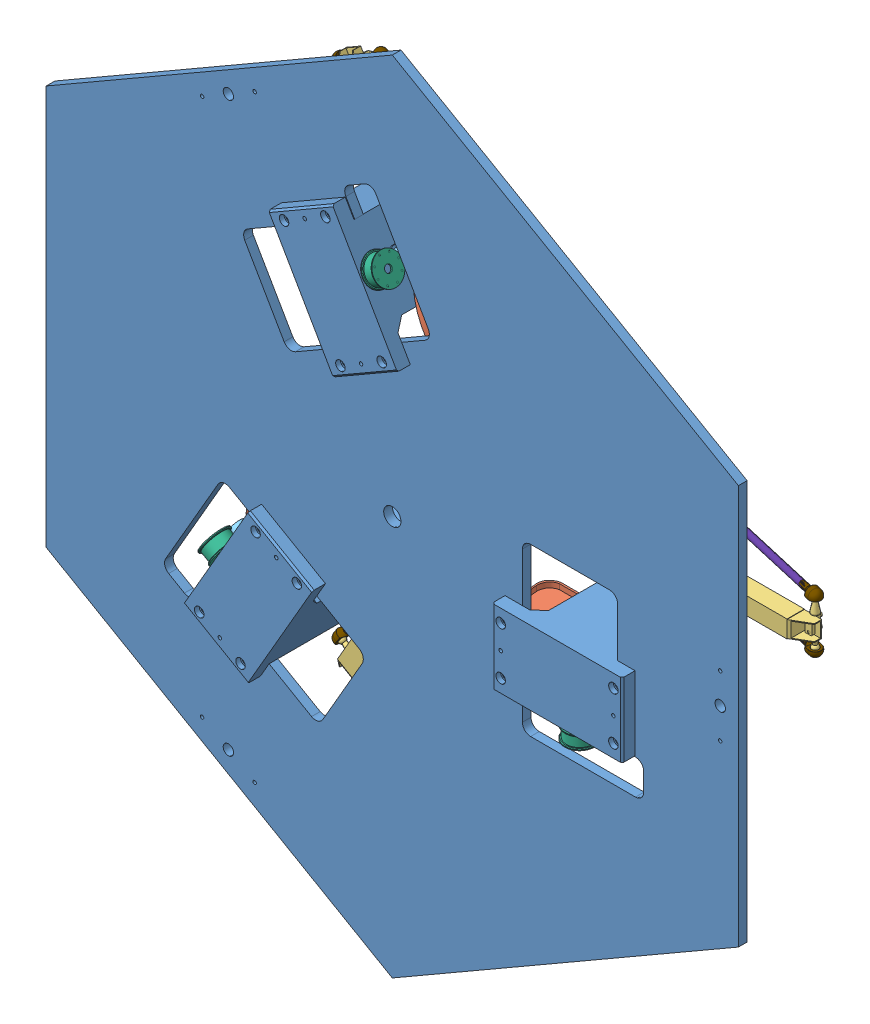
SolidWorks assembly RobotDelta - Copie, configuration Défaut. Lengths in mm.
Overall size (798.48 922 256.49).
65 component instances, 18 part files, 55 mates.
Components (placement in the parent):
- Pièce0_Base-1: Pièce0_Base [Défaut] at origin size (798.48 922 162.5)
- Pièce1_Roue_ecrou-3: Pièce1_Roue_ecrou [Défaut] at (12.4686 180.4038 -115) x (-0.499999 0.866024 -0.001524) z (0.866025 0.5 0) size (209.95 116.72 30.4)
- Pièce1_Roue_ecrou-4: Pièce1_Roue_ecrou [Défaut] at (150 -101 -115) x (0.999999 0 -0.001524) z (0 -1 0) size (209.95 116.72 30.4)
- Pièce1_Roue_ecrou-5: Pièce1_Roue_ecrou [Défaut] at (-162.4686 -79.4038 -115) x (-0.499999 -0.866024 -0.001524) z (-0.866025 0.5 0) size (209.95 116.72 30.4)
- Pièce0_Bras-2: Pièce0_Bras [Défaut] at (-66.3397 -134.9038 -115) x (0.499999 0.866024 0.001524) z (-0.866025 0.5 0) size (222 30.5 58)
- Pièce0_Bras-3: Pièce0_Bras [Défaut] at (150 10 -115) x (-0.999999 0 0.001524) z (0 -1 0) size (222 30.5 58)
- Pièce0_Bras-4: Pièce0_Bras [Défaut] at (-83.6603 124.9038 -115) x (0.499999 -0.866024 0.001524) z (0.866025 0.5 0) size (222 30.5 58)
- Pièce1_arbre-3: Pièce1_arbre [Défaut] at (150 -56.5 -115) x (0.999999 0 -0.001524) z (0 -1 0) size (15 15 157)
- Pièce1_arbre-4: Pièce1_arbre [Défaut] at (-123.9304 -101.6538 -115) x (0.499999 0.866024 0.001524) z (0.866025 -0.5 0) size (15 15 157)
- Pièce1_arbre-5: Pièce1_arbre [Défaut] at (-26.0696 158.1538 -115) x (0.499999 -0.866024 0.001524) z (-0.866025 -0.5 0) size (15 15 157)
- Pièce1_PignionModifie-4: Pièce1_PignionModifie [Défaut] at (214 -101 -18) x (1 0 0) z (0 -1 0) size (16.65 16.65 16)
- Pièce1_poulie_renvoie-3: Pièce1_poulie_renvoie [Défaut] at (214 -101 8) x (1 0 0) z (0 -1 0) size (34 34 15)
- Pièce1_PignionModifie-5: Pièce1_PignionModifie [Défaut] at (-194.4686 -134.8294 -18) x (0.25 0.433013 0.866025) z (-0.866025 0.5 0) size (16.65 16.65 16)
- Pièce1_poulie_renvoie-4: Pièce1_poulie_renvoie [Défaut] at (-194.4686 -134.8294 8) x (0.25 0.433013 0.866025) z (-0.866025 0.5 0) size (34 34 15)
- Pièce1_poulie_renvoie-5: Pièce1_poulie_renvoie [Défaut] at (-19.5314 235.8294 8) x (0.25 -0.433013 -0.866025) z (0.866025 0.5 0) size (34 34 15)
- Pièce1_PignionModifie-6: Pièce1_PignionModifie [Défaut] at (-19.5314 235.8294 -18) x (0.25 -0.433013 -0.866025) z (0.866025 0.5 0) size (16.65 16.65 16)
- Nacelle2-1: Nacelle2 [Défaut] at (0 0 -198.2626) x (-0.448789 -0.893638 0) z (0 0 -1) size (21.1 21.1 48)
  - Pièce5_BagueArret-1: Pièce5_BagueArret [Défaut] at (0 0 19) x (-0.629497 -0.777003 0) z (0 0 -1) size (15 15 3)
  - Pièce5_RaccordCardon-1: Pièce5_RaccordCardon [Défaut] at (0 0 -21) x (-0.946095 -0.32389 0) z (0 0 1) size (12 12 11)
  - Pièce5_Tube-1: Pièce5_Tube [Défaut] at (0 0 6.5) x (0 0 1) z (0.946095 0.32389 0) size (32 15 15)
  - Pièce5_Guide-1: Pièce5_Guide [Défaut] at (0 0 -3) x (0.946095 0.32389 0) z (0 0 -1) size (12.69 15 12)
- Nacelle1-1: Nacelle1 [Défaut] at (0 0 -203.2626) x (-0.866025 0.5 0) z (0 0 1) size (78.36 68.86 31.5)
  - Pièce5_Nacelle-1: Pièce5_Nacelle [Défaut] at origin size (49.34 42.73 10)
  - Pièce5_RaccordTuyau-1: Pièce5_RaccordTuyau [Défaut] at (0 -16.5885 0) x (1 0 0) z (0 1 0) size (8 24.5 10)
  - Pièce2_Articulation-1: Pièce2_Articulation [Défaut] at (0 24 0) size (58 9 9)
  - Pièce2_Articulation-2: Pièce2_Articulation [Défaut] at (-20.7846 -12 0) x (0.5 -0.866025 0) z (0 0 1) size (58 9 9)
  - Pièce2_Articulation-3: Pièce2_Articulation [Défaut] at (20.7846 -12 0) x (-0.5 -0.866025 0) z (0 0 1) size (58 9 9)
  - Pièce5_Capot-1: Pièce5_Capot [Défaut] at (0 0 11) x (-1 0 0) z (0 0 -1) size (28 28 7)
  - Pièce5_Capot-2: Pièce5_Capot [Défaut] at (0 0 -11) size (28 28 7)
  - Pièce5_ViceTcyM2.5_10-4: Pièce5_ViceTcyM2.5_10 [Défaut] at (0 11 -9.5) size (4 4 9.5)
  - Pièce5_ViceTcyM2.5_10-5: Pièce5_ViceTcyM2.5_10 [Défaut] at (-9.5263 -5.5 -9.5) size (4 4 9.5)
  - Pièce5_ViceTcyM2.5_10-6: Pièce5_ViceTcyM2.5_10 [Défaut] at (9.5263 -5.5 -9.5) size (4 4 9.5)
  - Pièce5_ViceTcyM3_10-1: Pièce5_ViceTcyM3_10 [Défaut] at (-6 29.5 0) x (1 0 0) z (0 -1 0) size (5.5 5.5 12.5)
  - Pièce5_ViceTcyM3_10-2: Pièce5_ViceTcyM3_10 [Défaut] at (6 29.5 0) x (1 0 0) z (0 -1 0) size (5.5 5.5 12.5)
  - Pièce5_ViceTcyM3_10-3: Pièce5_ViceTcyM3_10 [Défaut] at (28.5477 -9.5538 0) x (0.25 0.433013 0.866025) z (-0.866025 0.5 0) size (5.5 5.5 12.5)
  - Pièce5_ViceTcyM3_10-4: Pièce5_ViceTcyM3_10 [Défaut] at (22.5477 -19.9462 0) x (0.25 0.433013 0.866025) z (-0.866025 0.5 0) size (5.5 5.5 12.5)
  - Pièce5_ViceTcyM3_10-5: Pièce5_ViceTcyM3_10 [Défaut] at (-28.5477 -9.5538 0) x (0.25 -0.433013 -0.866025) z (0.866025 0.5 0) size (5.5 5.5 12.5)
  - Pièce5_ViceTcyM3_10-6: Pièce5_ViceTcyM3_10 [Défaut] at (-22.5477 -19.9462 0) x (0.25 -0.433013 -0.866025) z (0.866025 0.5 0) size (5.5 5.5 12.5)
  - Pièce5_ViceTcyM2.5_10-7: Pièce5_ViceTcyM2.5_10 [Défaut] at (9.5263 -5.5 9.5) x (-0.923728 -0.383049 0) z (0 0 -1) size (4 4 9.5)
  - Pièce5_ViceTcyM2.5_10-8: Pièce5_ViceTcyM2.5_10 [Défaut] at (0 11 9.5) x (-0.923728 -0.383049 0) z (0 0 -1) size (4 4 9.5)
  - Pièce5_ViceTcyM2.5_10-9: Pièce5_ViceTcyM2.5_10 [Défaut] at (-9.5263 -5.5 9.5) x (-0.627519 -0.778601 0) z (0 0 -1) size (4 4 9.5)
- BarreParalleles-1: BarreParalleles [Défaut] at (80.9117 -90.9235 -236.4802) x (-0.864926 -0.501816 0.009215) z (-0.487245 0.843934 0.224427) size (11.85 14 348)
  - Pièce4_Tube-1: Pièce4_Tube [Défaut] at (-2.2142 0.2364 157) size (7 7 314)
  - Pièce4_Extremetees-1: Pièce4_Extremetees [Défaut] at (-2.2142 0.2364 147) x (0 -1 0) z (0 0 1) size (14 11.85 27)
  - Pièce4_Extremetees-2: Pièce4_Extremetees [Défaut] at (-2.2142 0.2364 481) x (0 1 0) z (0 0 -1) size (14 11.85 27)
- BarreParalleles-2: BarreParalleles [Défaut] at (38.3384 -115.6238 -236.0266) x (0.864926 0.501816 -0.009215) z (-0.487245 0.843934 0.224427) size (11.85 14 348)
  - Pièce4_Tube-1: Pièce4_Tube [Défaut] at (-2.2142 0.2364 157) size (7 7 314)
  - Pièce4_Extremetees-1: Pièce4_Extremetees [Défaut] at (-2.2142 0.2364 147) x (0 -1 0) z (0 0 1) size (14 11.85 27)
  - Pièce4_Extremetees-2: Pièce4_Extremetees [Défaut] at (-2.2142 0.2364 481) x (0 1 0) z (0 0 -1) size (14 11.85 27)
- BarreParalleles-3: BarreParalleles [Défaut] at (80.964 91.014 -236.0266) x (-0.867048 0.49814 -0.009215) z (-0.487245 -0.843934 0.224427) size (11.85 14 348)
  - Pièce4_Tube-1: Pièce4_Tube [Défaut] at (-2.2142 0.2364 157) size (7 7 314)
  - Pièce4_Extremetees-1: Pièce4_Extremetees [Défaut] at (-2.2142 0.2364 147) x (0 -1 0) z (0 0 1) size (14 11.85 27)
  - Pièce4_Extremetees-2: Pièce4_Extremetees [Défaut] at (-2.2142 0.2364 481) x (0 1 0) z (0 0 -1) size (14 11.85 27)
- BarreParalleles-4: BarreParalleles [Défaut] at (38.2862 115.5334 -236.4802) x (0.867048 -0.49814 0.009215) z (-0.487245 -0.843934 0.224427) size (11.85 14 348)
  - Pièce4_Tube-1: Pièce4_Tube [Défaut] at (-2.2142 0.2364 157) size (7 7 314)
  - Pièce4_Extremetees-1: Pièce4_Extremetees [Défaut] at (-2.2142 0.2364 147) x (0 -1 0) z (0 0 1) size (14 11.85 27)
  - Pièce4_Extremetees-2: Pièce4_Extremetees [Défaut] at (-2.2142 0.2364 481) x (0 1 0) z (0 0 -1) size (14 11.85 27)
- BarreParalleles-5: BarreParalleles [Défaut] at (-119.3024 24.6099 -236.0266) x (0.002122 -0.999955 -0.009215) z (0.974491 0 0.224427) size (11.85 14 348)
  - Pièce4_Tube-1: Pièce4_Tube [Défaut] at (-2.2142 0.2364 157) size (7 7 314)
  - Pièce4_Extremetees-1: Pièce4_Extremetees [Défaut] at (-2.2142 0.2364 147) x (0 -1 0) z (0 0 1) size (14 11.85 27)
  - Pièce4_Extremetees-2: Pièce4_Extremetees [Défaut] at (-2.2142 0.2364 481) x (0 1 0) z (0 0 -1) size (14 11.85 27)
- BarreParalleles-6: BarreParalleles [Défaut] at (-119.1979 -24.6099 -236.4802) x (-0.002122 0.999955 0.009215) z (0.974491 0 0.224427) size (11.85 14 348)
  - Pièce4_Tube-1: Pièce4_Tube [Défaut] at (-2.2142 0.2364 157) size (7 7 314)
  - Pièce4_Extremetees-1: Pièce4_Extremetees [Défaut] at (-2.2142 0.2364 147) x (0 -1 0) z (0 0 1) size (14 11.85 27)
  - Pièce4_Extremetees-2: Pièce4_Extremetees [Défaut] at (-2.2142 0.2364 481) x (0 1 0) z (0 0 -1) size (14 11.85 27)
Mates (geometry in assembly coordinates):
- Coïncidente1: coincident anti-aligned: plane of Pièce0_Base-1 through (12.4686 180.4038 -115) normal (0.866025 0.5 0); plane of Pièce1_Roue_ecrou-3 through (12.4686 180.4038 -115) normal (-0.866025 -0.5 0)
- Coaxiale1: concentric anti-aligned: cylinder of Pièce0_Base-1 through (-62.8756 136.9038 -115) axis (0.866025 0.5 0) radius 5; cylinder of Pièce1_Roue_ecrou-3 through (38.7957 195.6038 -115) axis (-0.866025 -0.5 0) radius 5
- Coïncidente2: coincident anti-aligned: plane of Pièce0_Base-1 through (150 -101 -115) normal (0 -1 0); plane of Pièce1_Roue_ecrou-4 through (150 -101 -115) normal (0 1 0)
- Coaxiale4: concentric anti-aligned: cylinder of Pièce0_Base-1 through (150 -14 -115) axis (0 -1 0) radius 5; cylinder of Pièce1_Roue_ecrou-4 through (150 -136 -115) axis (0 1 0) radius 5
- Coïncidente3: coincident anti-aligned: plane of Pièce0_Base-1 through (-162.4686 -79.4038 -115) normal (-0.866025 0.5 0); plane of Pièce1_Roue_ecrou-5 through (-162.4686 -79.4038 -115) normal (0.866025 -0.5 0)
- Coaxiale5: concentric anti-aligned: cylinder of Pièce0_Base-1 through (-87.1244 -122.9038 -115) axis (-0.866025 0.5 0) radius 5; cylinder of Pièce1_Roue_ecrou-5 through (-192.7795 -61.9038 -115) axis (0.866025 -0.5 0) radius 5
- Coïncidente4: coincident anti-aligned: plane of Pièce0_Base-1 through (-83.6603 -124.9038 -115) normal (0.866025 -0.5 0); plane of Pièce0_Bras-2 through (-83.6603 -124.9038 -115) normal (-0.866025 0.5 0)
- Coaxiale6: concentric anti-aligned: cylinder of Pièce0_Base-1 through (-87.1244 -122.9038 -115) axis (-0.866025 0.5 0) radius 5; cylinder of Pièce0_Bras-2 through (-83.6603 -124.9038 -115) axis (0.866025 -0.5 0) radius 6
- Coïncidente5: coincident anti-aligned: plane of Pièce0_Base-1 through (150 -10 -115) normal (0 1 0); plane of Pièce0_Bras-3 through (150 -10 -115) normal (0 -1 0)
- Coaxiale7: concentric anti-aligned: cylinder of Pièce0_Base-1 through (150 -14 -115) axis (0 -1 0) radius 5; cylinder of Pièce0_Bras-3 through (150 -10 -115) axis (0 1 0) radius 6
- Coïncidente6: coincident anti-aligned: plane of Pièce0_Base-1 through (-66.3397 134.9038 -115) normal (-0.866025 -0.5 0); plane of Pièce0_Bras-4 through (-66.3397 134.9038 -115) normal (0.866025 0.5 0)
- Coaxiale8: concentric anti-aligned: cylinder of Pièce0_Base-1 through (-62.8756 136.9038 -115) axis (0.866025 0.5 0) radius 5; cylinder of Pièce0_Bras-4 through (-66.3397 134.9038 -115) axis (-0.866025 -0.5 0) radius 6
- Parallèle1: parallel aligned: plane of Pièce1_Roue_ecrou-3 through (26.3338 188.3885 -126.596) normal (0.000762 -0.00132 -0.999999); plane of Pièce0_Bras-4 through (-66.3306 134.888 -127) normal (0.000762 -0.00132 -0.999999)
- Parallèle2: parallel aligned: plane of Pièce1_Roue_ecrou-5 through (-176.3161 -71.3885 -126.596) normal (0.000762 0.00132 -0.999999); plane of Pièce0_Bras-2 through (-83.6511 -124.888 -127) normal (0.000762 0.00132 -0.999999)
- Parallèle3: parallel aligned: plane of Pièce1_Roue_ecrou-4 through (149.9823 -117 -126.596) normal (-0.001524 0 -0.999999); plane of Pièce0_Bras-3 through (149.9817 -10 -127) normal (-0.001524 0 -0.999999)
- Coaxiale10: concentric anti-aligned: cylinder of Pièce0_Bras-3 through (150 -10 -115) axis (0 1 0) radius 6; cylinder of Pièce1_arbre-3 through (150 -99 -115) axis (0 -1 0) radius 7.5
- Coïncidente10: coincident aligned: plane of Pièce0_Base-1 through (214 -14 -18) normal (0 1 0); plane of Pièce1_arbre-3 through (150 -14 -115) normal (0 1 0)
- Parallèle4: parallel anti-aligned: plane of Pièce0_Bras-3 through (150.0183 -10 -103) normal (0.001524 0 0.999999); plane of Pièce1_arbre-3 through (155.8346 21.5 -114.1773) normal (-0.001524 0 -0.999999)
- Coaxiale11: concentric anti-aligned: cylinder of Pièce0_Bras-2 through (-57.3331 -140.1038 -115) axis (-0.866025 0.5 0) radius 5; cylinder of Pièce1_arbre-4 through (-87.1244 -122.9038 -115) axis (0.866025 -0.5 0) radius 7.5
- Coïncidente12: coincident aligned: plane of Pièce0_Base-1 through (-119.1244 -178.3294 -18) normal (0.866025 -0.5 0); plane of Pièce1_arbre-4 through (-87.1244 -122.9038 -115) normal (0.866025 -0.5 0)
- Parallèle5: parallel aligned: plane of Pièce0_Bras-2 through (-83.6511 -124.888 -127) normal (0.000762 0.00132 -0.999999); plane of Pièce1_arbre-4 through (-53.4644 -135.6031 -114.1596) normal (0.000762 0.00132 -0.999999)
- Coaxiale12: concentric anti-aligned: cylinder of Pièce0_Bras-4 through (-92.6669 119.7038 -115) axis (0.866025 0.5 0) radius 5; cylinder of Pièce1_arbre-5 through (-62.8756 136.9038 -115) axis (-0.866025 -0.5 0) radius 7.5
- Coïncidente14: coincident aligned: plane of Pièce0_Base-1 through (-94.8756 192.3294 -18) normal (-0.866025 -0.5 0); plane of Pièce1_arbre-5 through (-62.8756 136.9038 -115) normal (-0.866025 -0.5 0)
- Parallèle6: parallel: plane of Pièce0_Bras-4 through (-66.3306 134.888 -127) normal (0.000762 -0.00132 -0.999999); line of Pièce1_arbre-5 through (-96.5184 123.1747 -114.176) axis (0.499999 -0.866024 0.001524)
- Coïncidente16: coincident anti-aligned: plane of Pièce0_Base-1 through (214 -101 8) normal (0 -1 0); plane of Pièce1_poulie_renvoie-3 through (214 -101 8) normal (0 1 0)
- Coïncidente18: coincident anti-aligned: plane of Pièce0_Base-1 through (214 -101 -18) normal (0 -1 0); plane of Pièce1_PignionModifie-4 through (214 -101 -18) normal (0 1 0)
- Coaxiale13: concentric aligned: cylinder of Pièce0_Base-1 through (214 -114 -18) axis (0 1 0) radius 5; cylinder of Pièce1_PignionModifie-4 through (214 -117 -18) axis (0 1 0) radius 5
- Coaxiale14: concentric anti-aligned: cylinder of Pièce0_Base-1 through (214 -114 8) axis (0 1 0) radius 4; cylinder of Pièce1_poulie_renvoie-3 through (214 -116 8) axis (0 -1 0) radius 4
- Coaxiale15: concentric anti-aligned: cylinder of Pièce0_Base-1 through (-205.7269 -128.3294 8) axis (0.866025 -0.5 0) radius 4; cylinder of Pièce1_poulie_renvoie-4 through (-207.4589 -127.3294 8) axis (-0.866025 0.5 0) radius 4
- Coaxiale16: concentric aligned: cylinder of Pièce0_Base-1 through (-205.7269 -128.3294 -18) axis (0.866025 -0.5 0) radius 5; cylinder of Pièce1_PignionModifie-5 through (-208.325 -126.8294 -18) axis (0.866025 -0.5 0) radius 5
- Coïncidente19: coincident anti-aligned: plane of Pièce0_Base-1 through (-194.4686 -134.8294 8) normal (-0.866025 0.5 0); plane of Pièce1_poulie_renvoie-4 through (-194.4686 -134.8294 8) normal (0.866025 -0.5 0)
- Coïncidente20: coincident anti-aligned: plane of Pièce0_Base-1 through (-194.4686 -134.8294 -18) normal (-0.866025 0.5 0); plane of Pièce1_PignionModifie-5 through (-194.4686 -134.8294 -18) normal (0.866025 -0.5 0)
- Coaxiale17: concentric aligned: cylinder of Pièce0_Base-1 through (-8.2731 242.3294 -18) axis (-0.866025 -0.5 0) radius 5; cylinder of Pièce1_PignionModifie-6 through (-5.675 243.8294 -18) axis (-0.866025 -0.5 0) radius 5
- Coaxiale18: concentric anti-aligned: cylinder of Pièce0_Base-1 through (-8.2731 242.3294 8) axis (-0.866025 -0.5 0) radius 4; cylinder of Pièce1_poulie_renvoie-5 through (-6.5411 243.3294 8) axis (0.866025 0.5 0) radius 4
- Coïncidente22: coincident anti-aligned: plane of Pièce0_Base-1 through (-19.5314 235.8294 8) normal (0.866025 0.5 0); plane of Pièce1_poulie_renvoie-5 through (-19.5314 235.8294 8) normal (-0.866025 -0.5 0)
- Coïncidente23: coincident anti-aligned: plane of Pièce0_Base-1 through (-19.5314 235.8294 -18) normal (0.866025 0.5 0); plane of Pièce1_PignionModifie-6 through (-19.5314 235.8294 -18) normal (-0.866025 -0.5 0)
- Coaxiale19: concentric anti-aligned: cylinder of Nacelle2-1/Pièce5_Tube-1 through (0 0 -186.0604) axis (0 0 1) radius 6; cylinder of Nacelle1-1/Pièce5_Capot-2 through (0 0 -207.2626) axis (0 0 -1) radius 6
- Coïncidente24: coincident anti-aligned: plane of Nacelle2-1/Pièce5_BagueArret-1 through (0 0 -214.2626) normal (0 0 1); plane of Nacelle1-1/Pièce5_Capot-2 through (0 0 -214.2626) normal (0 0 -1)
- Parallèle7: parallel anti-aligned: plane of Pièce0_Base-1 through (0 0 10) normal (0 0 1); plane of Nacelle1-1/Pièce5_Nacelle-1 through (0 0 -208.2626) normal (0 0 -1)
- Coaxiale23: concentric: sphere of Pièce0_Bras-3; sphere of BarreParalleles-5/Pièce4_Extremetees-2
- Coaxiale24: concentric: sphere of Pièce0_Bras-3; sphere of BarreParalleles-6/Pièce4_Extremetees-2
- Coaxiale25: concentric: sphere of Pièce0_Bras-2; sphere of BarreParalleles-3/Pièce4_Extremetees-2
- Coaxiale26: concentric: sphere of Pièce0_Bras-2; sphere of BarreParalleles-4/Pièce4_Extremetees-2
- Coaxiale27: concentric: sphere of Pièce0_Bras-4; sphere of BarreParalleles-1/Pièce4_Extremetees-2
- Coaxiale28: concentric: sphere of Pièce0_Bras-4; sphere of BarreParalleles-2/Pièce4_Extremetees-2
- Coïncidente27: coincident anti-aligned: plane of BarreParalleles-1; plane of BarreParalleles-2
- Coïncidente28: coincident anti-aligned: plane of BarreParalleles-3; plane of BarreParalleles-4
- Coïncidente31: coincident anti-aligned: plane of BarreParalleles-5; plane of BarreParalleles-6
- Coaxiale29: concentric: sphere of Nacelle1-1/Pièce2_Articulation-3; sphere of BarreParalleles-1/Pièce4_Extremetees-1
- Coaxiale30: concentric: sphere of Nacelle1-1/Pièce2_Articulation-3; sphere of BarreParalleles-2/Pièce4_Extremetees-1
- Coaxiale31: concentric: sphere of Nacelle1-1/Pièce2_Articulation-2; sphere of BarreParalleles-5/Pièce4_Extremetees-1
- Coaxiale32: concentric: sphere of Nacelle1-1/Pièce2_Articulation-2; sphere of BarreParalleles-6/Pièce4_Extremetees-1
- Coaxiale33: concentric: sphere of Nacelle1-1/Pièce2_Articulation-1; sphere of BarreParalleles-3/Pièce4_Extremetees-1
- Coaxiale34: concentric: sphere of Nacelle1-1/Pièce2_Articulation-1; sphere of BarreParalleles-4/Pièce4_Extremetees-1
- Coaxiale35: concentric aligned: circle of Pièce0_Base-1; circle of Nacelle2-1/Pièce5_Tube-1
